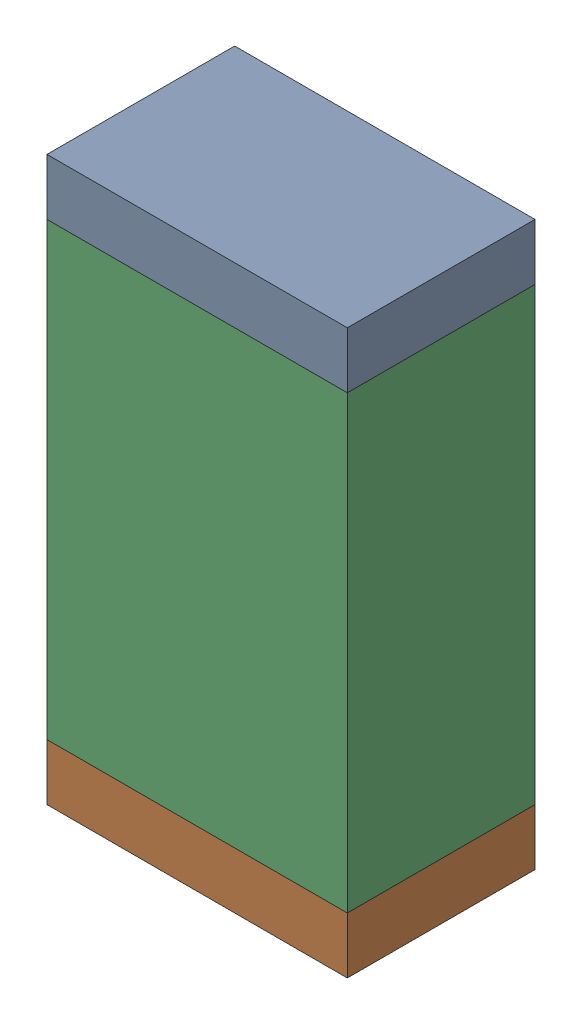
SolidWorks assembly R36, configuration Default. Lengths in mm.
Overall size (0.8 1.5 0.5).
6 component instances, 2 part files, 0 mates.
Components (placement in the parent):
- 810156592-1: 810156592 [Default] at (117.95 51.525 0) size (0.8 0.15 0.5)
  - Extruded_7-1: Extruded_7 [Default] at origin size (0.8 0.15 0.5)
- 810156592-2: 810156592 [Default] at (117.95 50.175 0) size (0.8 0.15 0.5)
  - Extruded_7-1: Extruded_7 [Default] at origin size (0.8 0.15 0.5)
- 810156976-1: 810156976 [Default] at (117.95 50.85 0) size (0.8 1.2 0.5)
  - Extruded_6-1: Extruded_6 [Default] at origin size (0.8 1.2 0.5)
